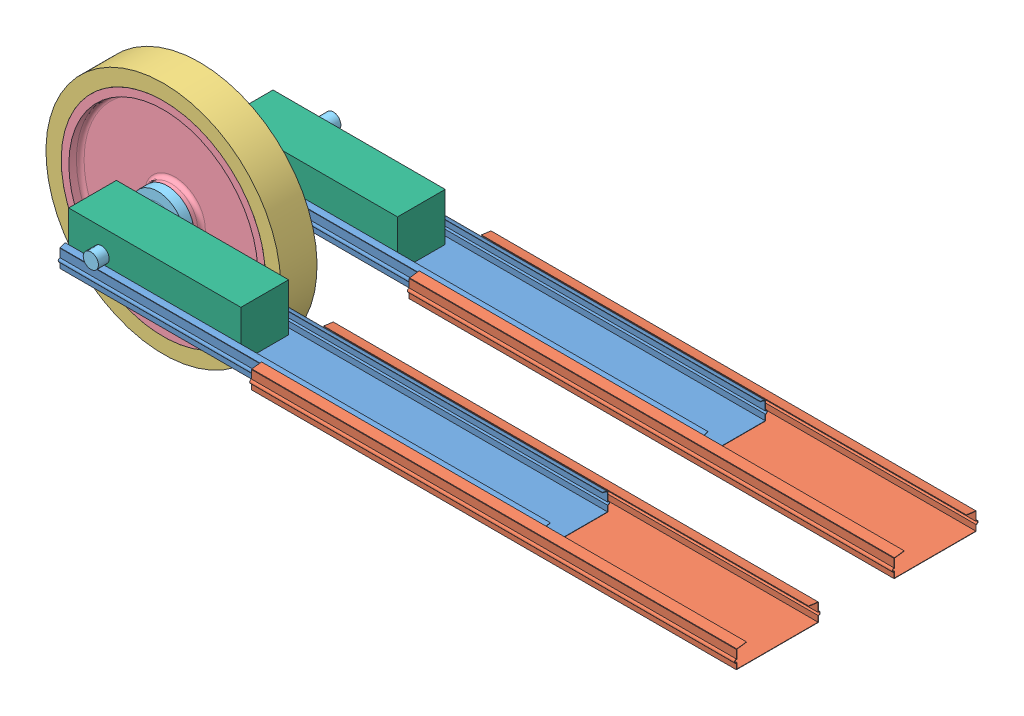
SolidWorks assembly wheel_sys, configuration Default. Lengths in mm.
Overall size (427.17 170.74 131.58).
12 component instances, 6 part files, 11 mates.
Components (placement in the parent):
- slider-1: slider [Default] at (295.7545 161.9821 248.2331) size (359 10.5 44.88)
  - inner slider-1: inner slider [Default] at (-151.895 -7.559 16.8408) size (254 10.3 34.88)
  - outer slider-1: outer slider [Default] at (-46.895 -7.759 16.5388) size (254 10.08 44.88)
- wheelwithaxle-1: wheelwithaxle [Default] at (804.7391 46.5563 384.5567) x (0.829197 -0.558957 0) z (-0.558957 -0.829197 0) size (123 127 123)
  - rim-1: rim [Default] at (-711.4248 -76.2879 334.1654) size (123 19 123)
  - centre-1: centre [Default] at (-711.4248 -76.2879 334.1654) size (107 19 107)
  - wheel axle-1: wheel axle [Default] at (-713.6031 -81.7741 334.1654) size (28 127 28)
- slider-2: slider [Default] at (295.7545 161.9821 330.8673) size (359 10.5 44.88)
  - inner slider-1: inner slider [Default] at (-151.895 -7.559 16.8408) size (254 10.3 34.88)
  - outer slider-1: outer slider [Default] at (-46.895 -7.759 16.5388) size (254 10.08 44.88)
- support-1: support [Default] at (-18.9561 167.1231 347.1618) x (0 -1 0) z (0 0 1) size (25 90.2 25)
- support-2: support [Default] at (-18.9561 167.1231 265.119) x (0 -1 0) z (0 0 1) size (25 90.2 25)
Mates (geometry in assembly coordinates):
- Coincident1: coincident anti-aligned: plane of slider-1/inner slider-1 through (143.8596 154.6231 265.0738) normal (0 1 0); plane of support-2 through (101.0439 154.6231 252.619) normal (0 -1 0)
- Coincident2: coincident anti-aligned: plane of slider-2/inner slider-1 through (143.8596 154.6231 347.7081) normal (0 1 0); plane of support-1 through (101.0439 154.6231 334.6618) normal (0 -1 0)
- Concentric1: concentric aligned: cylinder of wheelwithaxle-1/wheel axle-1 through (28.0439 167.1231 365.2688) axis (0 0 1) radius 4; circle of support-2
- Coincident7: coincident aligned: plane of slider-1/inner slider-1 through (10.8414 154.6231 248.5738) normal (-1 0 0); plane of support-2 through (10.8414 183.309 216.859) normal (-1 0 0)
- Coincident8: coincident aligned: plane of slider-2/inner slider-1 through (10.8414 154.6231 331.2081) normal (-1 0 0); plane of support-1 through (10.8414 183.309 298.9018) normal (-1 0 0)
- Distance1: distance = 40 mm: line of slider-1/outer slider-1 through (369.8414 163.6253 286.089) axis (-1 0 0); line of slider-2/outer slider-1 through (369.8414 163.6253 326.089) axis (-1 0 0)
- Coincident10: coincident aligned: plane of slider-1/outer slider-1 through (248.8596 154.4231 264.7718) normal (0 1 0); plane of slider-2/outer slider-1 through (248.8596 154.4231 347.4061) normal (0 1 0)
- Coincident11: coincident aligned: plane of slider-1/outer slider-1 through (369.8414 154.4231 243.2718) normal (1 0 0); plane of slider-2/outer slider-1 through (369.8414 154.4231 325.9061) normal (1 0 0)
- Distance3: distance = 3.7517 mm: line of slider-1/inner slider-1 through (264.8414 154.6231 281.3706) axis (-1 0 0); line of support-2 through (101.0439 154.6231 277.619) axis (-1 0 0)
- Distance4: distance = 4.3431 mm: line of support-1 through (101.0439 154.6231 359.6618) axis (-1 0 0); line of slider-2/inner slider-1 through (264.8414 154.6231 364.0049) axis (-1 0 0)
- Tangent2: tangent anti-aligned: plane of wheelwithaxle-1/wheel axle-1 through (31.3606 164.8873 330.2688) normal (0 0 1); cylinder of slider-2/inner slider-1 through (264.8414 158.368 331.2081) axis (-1 0 0) radius 0.9393
